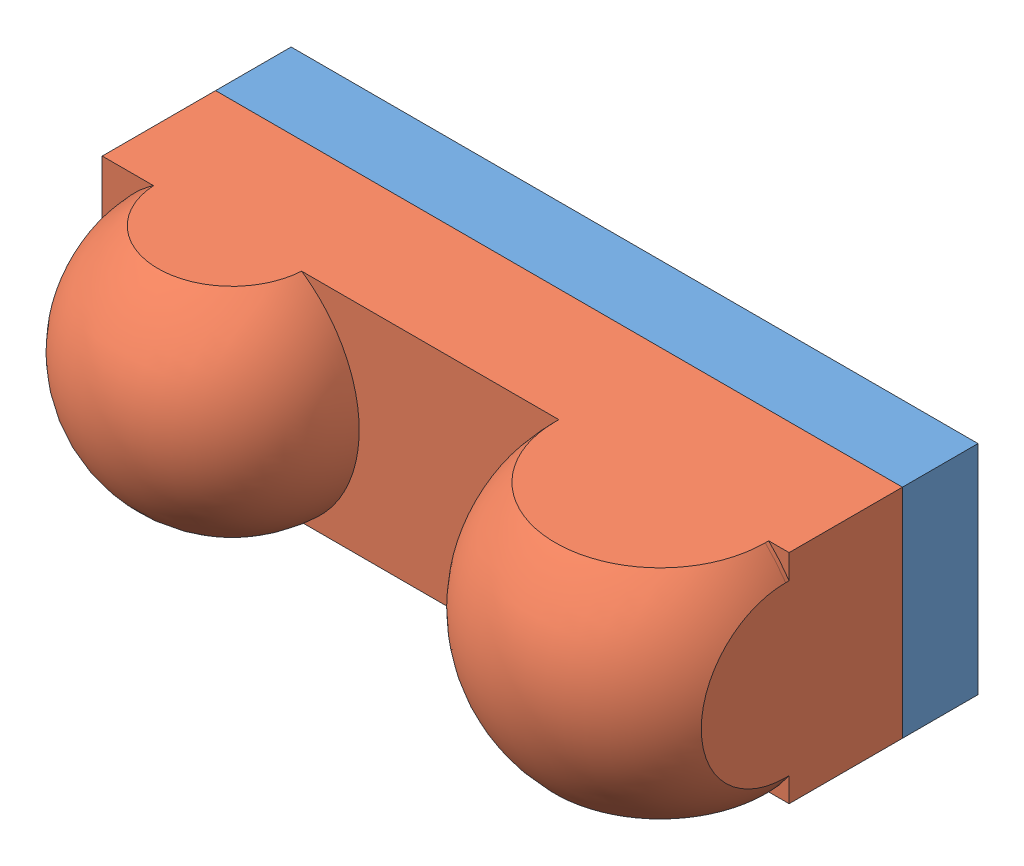
SolidWorks assembly User Library-TFBS4711, configuration Default. Lengths in mm.
Overall size (6 2.64 3.03).
8 component instances, 3 part files, 0 mates.
Components (placement in the parent):
- User Library-TFBS4711_PLATINE-1: User Library-TFBS4711_PLATINE [Default] at (460.1067 351.5107 0.33) size (6 1.9 0.66)
- User Library-TFBS4711_GEHAEUSE-1: User Library-TFBS4711_GEHAEUSE [Default] at (460.1067 351.5107 1.155) size (6 2.64 2.34)
- User Library-TFBS4711_KONTAKT-1: User Library-TFBS4711_KONTAKT [Default] at (457.7367 350.7707 -0.015) size (0.58 0.42 0.72)
- User Library-TFBS4711_KONTAKT-2: User Library-TFBS4711_KONTAKT [Default] at (458.6867 350.7707 -0.015) size (0.58 0.42 0.72)
- User Library-TFBS4711_KONTAKT-3: User Library-TFBS4711_KONTAKT [Default] at (459.6367 350.7707 -0.015) size (0.58 0.42 0.72)
- User Library-TFBS4711_KONTAKT-4: User Library-TFBS4711_KONTAKT [Default] at (460.5867 350.7707 -0.015) size (0.58 0.42 0.72)
- User Library-TFBS4711_KONTAKT-5: User Library-TFBS4711_KONTAKT [Default] at (461.5367 350.7707 -0.015) size (0.58 0.42 0.72)
- User Library-TFBS4711_KONTAKT-6: User Library-TFBS4711_KONTAKT [Default] at (462.4867 350.7707 -0.015) size (0.58 0.42 0.72)
